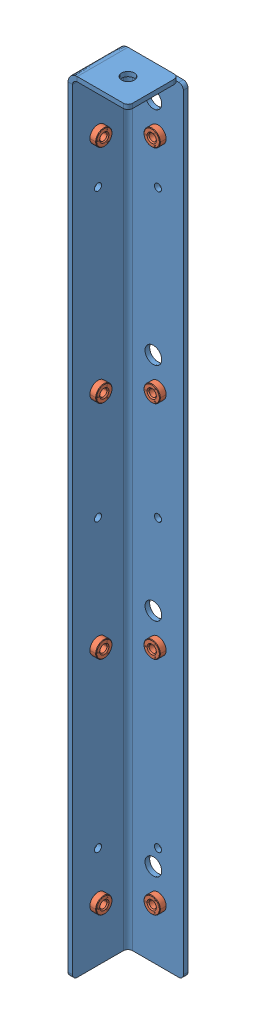
SolidWorks assembly GE-25106, configuration Default. Lengths in mm.
Overall size (41.27 540 41.27).
9 component instances, 2 part files, 19 mates.
Components (placement in the parent):
- GE-25106-01-1: GE-25106-01 [Above ramp] at (3.175 -273.304 3.175) size (41.27 540 41.27)
- pem_clinchnut_.25_20_.054-1: pem_clinchnut_.25_20_.054 [Default] at (1.8034 -44.45 23.8125) size (5.69 11.18 11.18)
- pem_clinchnut_.25_20_.054-2: pem_clinchnut_.25_20_.054 [Default] at (23.8125 -44.704 1.8034) x (0 0 1) z (-1 0 0) size (5.69 11.18 11.18)
- pem_clinchnut_.25_20_.054-3: pem_clinchnut_.25_20_.054 [Default] at (23.8125 -197.104 1.8034) x (0 0 1) z (-1 0 0) size (5.69 11.18 11.18)
- pem_clinchnut_.25_20_.054-4: pem_clinchnut_.25_20_.054 [Default] at (1.8034 -196.9347 23.8125) size (5.69 11.18 11.18)
- pem_clinchnut_.25_20_.054-5: pem_clinchnut_.25_20_.054 [Default] at (23.8125 -349.504 1.8034) x (0 0 1) z (-1 0 0) size (5.69 11.18 11.18)
- pem_clinchnut_.25_20_.054-6: pem_clinchnut_.25_20_.054 [Default] at (1.8034 -349.4193 23.8125) size (5.69 11.18 11.18)
- pem_clinchnut_.25_20_.054-7: pem_clinchnut_.25_20_.054 [Default] at (23.8125 -501.904 1.8034) x (0 0 1) z (-1 0 0) size (5.69 11.18 11.18)
- pem_clinchnut_.25_20_.054-8: pem_clinchnut_.25_20_.054 [Default] at (1.8034 -501.904 23.8125) size (5.69 11.18 11.18)
Mates (geometry in assembly coordinates):
- Coincident19: coincident anti-aligned: plane of ramp_innercornerbracket_plasticplastic-1 through (41.275 -6.604 3.175) normal (0 0 1); plane of pem_clinchnut_.25_20_.054-2 through (21.0185 -44.704 3.175) normal (0 0 -1)
- Coincident20: coincident anti-aligned: plane of ramp_innercornerbracket_plasticplastic-1 through (3.175 -6.604 3.175) normal (1 0 0); plane of pem_clinchnut_.25_20_.054-1 through (3.175 -44.45 26.6065) normal (-1 0 0)
- Coincident21: coincident anti-aligned: plane of ramp_innercornerbracket_plasticplastic-1 through (3.175 -6.604 3.175) normal (1 0 0); plane of pem_clinchnut_.25_20_.054-8 through (3.175 -501.904 26.6065) normal (-1 0 0)
- Coincident22: coincident anti-aligned: plane of ramp_innercornerbracket_plasticplastic-1 through (41.275 -6.604 3.175) normal (0 0 1); plane of pem_clinchnut_.25_20_.054-7 through (21.0185 -501.904 3.175) normal (0 0 -1)
- Coincident23: coincident anti-aligned: plane of ramp_innercornerbracket_plasticplastic-1 through (41.275 -6.604 3.175) normal (0 0 1); plane of pem_clinchnut_.25_20_.054-5 through (21.0185 -349.504 3.175) normal (0 0 -1)
- Coincident24: coincident anti-aligned: plane of ramp_innercornerbracket_plasticplastic-1 through (3.175 -6.604 3.175) normal (1 0 0); plane of pem_clinchnut_.25_20_.054-6 through (3.175 -349.4193 26.6065) normal (-1 0 0)
- Coincident25: coincident anti-aligned: plane of ramp_innercornerbracket_plasticplastic-1 through (41.275 -6.604 3.175) normal (0 0 1); plane of pem_clinchnut_.25_20_.054-3 through (21.0185 -197.104 3.175) normal (0 0 -1)
- Coincident26: coincident anti-aligned: plane of ramp_innercornerbracket_plasticplastic-1 through (3.175 -6.604 3.175) normal (1 0 0); plane of pem_clinchnut_.25_20_.054-4 through (3.175 -196.9347 26.6065) normal (-1 0 0)
- Coincident27: coincident anti-aligned: plane of ramp_innercornerbracket_plasticplastic-1 through (0 -6.604 3.175) normal (-1 0 0)
- Coincident28: coincident anti-aligned: plane of ramp_innercornerbracket_plasticplastic-1 through (41.275 -6.604 0) normal (0 0 -1)
- Coincident29: coincident aligned: plane of ramp_innercornerbracket_plasticplastic-1 through (3.175 0 3.175) normal (0 1 0)
- Concentric18: concentric aligned: cylinder of ramp_innercornerbracket_plasticplastic-1 through (23.8125 -501.904 3.175) axis (0 0 1) radius 4.3656; cylinder of pem_clinchnut_.25_20_.054-7 through (23.8125 -501.904 5.1664) axis (0 0 1) radius 5.588
- Concentric19: concentric aligned: cylinder of ramp_innercornerbracket_plasticplastic-1 through (23.8125 -349.504 3.175) axis (0 0 1) radius 4.3656; cylinder of pem_clinchnut_.25_20_.054-5 through (23.8125 -349.504 5.1664) axis (0 0 1) radius 5.588
- Concentric20: concentric aligned: cylinder of ramp_innercornerbracket_plasticplastic-1 through (23.8125 -197.104 3.175) axis (0 0 1) radius 4.3656; cylinder of pem_clinchnut_.25_20_.054-3 through (23.8125 -197.104 5.1664) axis (0 0 1) radius 5.588
- Concentric21: concentric aligned: cylinder of ramp_innercornerbracket_plasticplastic-1 through (23.8125 -44.704 3.175) axis (0 0 1) radius 4.3656; cylinder of pem_clinchnut_.25_20_.054-2 through (23.8125 -44.704 5.1664) axis (0 0 1) radius 5.588
- Concentric22: concentric aligned: cylinder of ramp_innercornerbracket_plasticplastic-1 through (3.175 -501.904 23.8125) axis (1 0 0) radius 4.3656; cylinder of pem_clinchnut_.25_20_.054-8 through (5.1664 -501.904 23.8125) axis (1 0 0) radius 5.588
- Concentric23: concentric aligned: cylinder of ramp_innercornerbracket_plasticplastic-1 through (3.175 -349.4193 23.8125) axis (1 0 0) radius 4.3656; cylinder of pem_clinchnut_.25_20_.054-6 through (5.1664 -349.4193 23.8125) axis (1 0 0) radius 5.588
- Concentric24: concentric aligned: cylinder of pem_clinchnut_.25_20_.054-4 through (5.1664 -196.9347 23.8125) axis (1 0 0) radius 5.588; cylinder of ramp_innercornerbracket_plasticplastic-1 through (3.175 -196.9347 23.8125) axis (1 0 0) radius 4.3656
- Concentric25: concentric aligned: cylinder of ramp_innercornerbracket_plasticplastic-1 through (3.175 -44.45 23.8125) axis (1 0 0) radius 4.3656; cylinder of pem_clinchnut_.25_20_.054-1 through (5.1664 -44.45 23.8125) axis (1 0 0) radius 5.588
